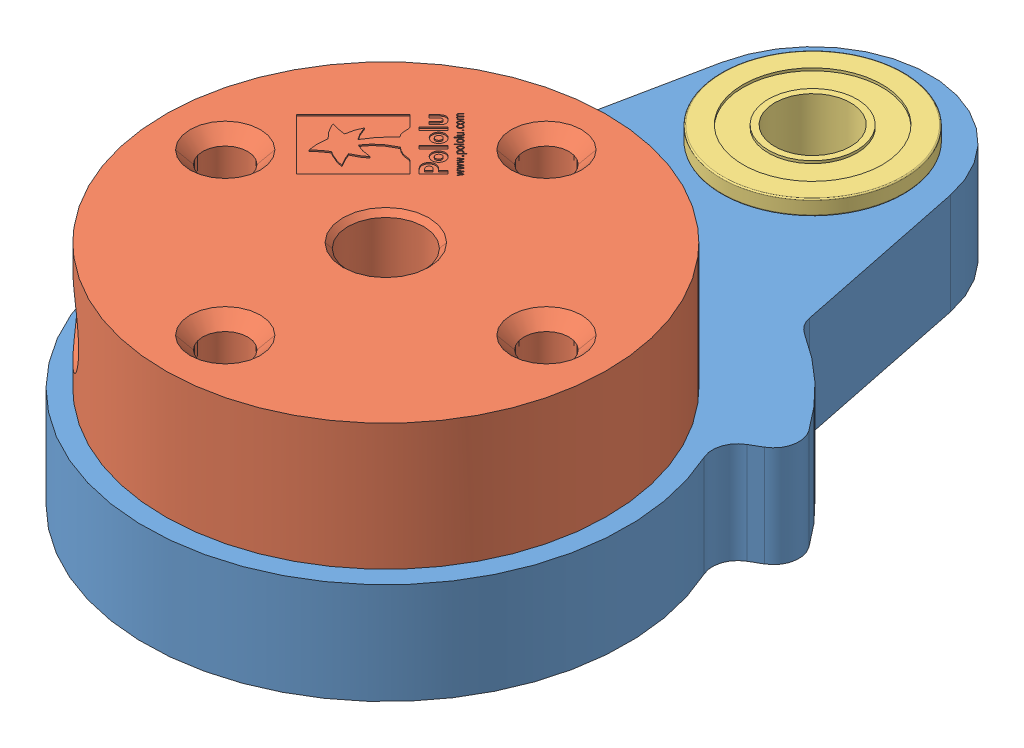
SolidWorks assembly Spider_lever, configuration Default. Lengths in mm.
Overall size (24.75 9.6 33.88).
4 component instances, 3 part files, 7 mates.
Components (placement in the parent):
- SLS_Lever_upper-1: SLS_Lever_upper [Default] at origin size (20.83 4 31)
- shaft_mount-1: shaft_mount [Default] at (-0.0001 6.4999 0.0001) x (-0.707107 0 -0.707107) z (0 1 0) size (17.5 17.5 5)
- MF63zz 3x6x2.5mm Flanged Bearing.step-1: MF63zz 3x6x2.5mm Flanged Bearing.step [Default] at (0 4.6 -16.8746) x (1 0 0) z (0 -1 0) size (7.2 7.2 2.5)
- MF63zz 3x6x2.5mm Flanged Bearing.step-2: MF63zz 3x6x2.5mm Flanged Bearing.step [Default] at (0 -0.6 -16.8746) x (-1 0 0) z (0 1 0) size (7.2 7.2 2.5)
Mates (geometry in assembly coordinates):
- Concentric1: concentric anti-aligned: cylinder of SLS_Lever_upper-1 through (0 0 -6.35) axis (0 1 0) radius 1.3; cylinder of shaft_mount-1 through (0 4 -6.35) axis (0 -1 0) radius 0.889
- Concentric2: concentric anti-aligned: cylinder of SLS_Lever_upper-1 through (0 0 6.35) axis (0 1 0) radius 1.3; cylinder of shaft_mount-1 through (0 4 6.35) axis (0 -1 0) radius 0.889
- Coincident1: coincident anti-aligned: plane of SLS_Lever_upper-1 through (0 4 -16.8746) normal (0 1 0); plane of shaft_mount-1 through (0 4 0) normal (0 -1 0)
- Concentric3: concentric aligned: circle of SLS_Lever_upper-1; cylinder of MF63zz 3x6x2.5mm Flanged Bearing.step-1 through (0 3.05 -16.8746) axis (0 1 0) radius 3
- Coincident2: coincident anti-aligned: plane of SLS_Lever_upper-1 through (0 4 -16.8746) normal (0 1 0); plane of MF63zz 3x6x2.5mm Flanged Bearing.step-1 through (-3.6 4 -16.8746) normal (0 -1 0)
- Concentric4: concentric aligned: cylinder of SLS_Lever_upper-1 through (0 4 -16.8746) axis (0 -1 0) radius 3.05; cylinder of MF63zz 3x6x2.5mm Flanged Bearing.step-2 through (0 0.95 -16.8746) axis (0 -1 0) radius 3
- Coincident3: coincident anti-aligned: plane of SLS_Lever_upper-1 through (0 0 -16.8746) normal (0 -1 0); plane of MF63zz 3x6x2.5mm Flanged Bearing.step-2 through (3.6 0 -16.8746) normal (0 1 0)
